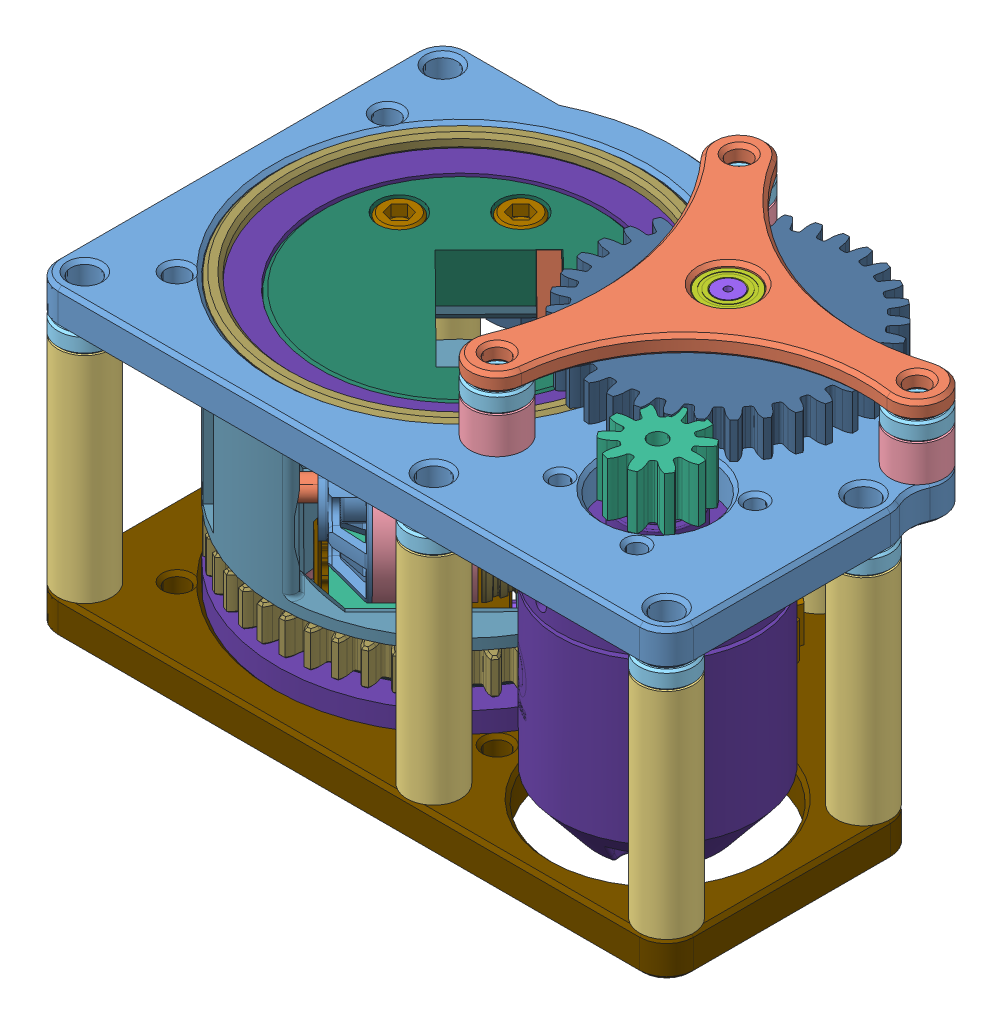
SolidWorks assembly Teathered Swerve Outer Modual Assem, configuration Default. Lengths in mm.
Overall size (127.68 94.78 93.36).
160 component instances, 50 part files, 75 mates.
Components (placement in the parent):
- Teathered Swerve Outer Modual-1: Teathered Swerve Outer Modual [Sketch Only] at origin
- Teathered Swerve Assem-1: Teathered Swerve Assem [Default] at (0 19.05 0) x (0.703653 0 -0.710544) z (0.710544 0 0.703653) size (65 79.59 67.05)
  - Teathered Swerve Inner Structure-1: Teathered Swerve Inner Structure [Default] at origin
  - BA-2310-Motor.STEP-1: BA-2310-Motor.STEP [Default] at (13.218 51.7723 56.3355) x (0 0.707107 0.707107) z (-1 0 0) size (29.1 29.1 46)
    - 2310-Rotor-Assem.STEP-1: 2310-Rotor-Assem.STEP [Default] at (14.7295 2.66 3.5453) size (29.1 29.1 46)
      - 23mm-Endbell.STEP-1: 23mm-Endbell.STEP [Default] at (-57.7218 14.2616 14.8949) size (29.1 29.1 12.75)
      - 2310-Shaft.STEP-1: 2310-Shaft.STEP [Default] at (-57.7218 14.2616 -15.3551) size (4 4 46)
      - 2310-Magnet.STEP-1: 2310-Magnet.STEP [Default] at (-57.7218 14.2616 8.6449) size (4 1.65 10)
      - 2310-Magnet.STEP-2: 2310-Magnet.STEP [Default] at (-57.7218 14.2616 8.6449) x (0.900969 0.433884 0) z (0 0 1) size (4 1.65 10)
      - 2310-Magnet.STEP-3: 2310-Magnet.STEP [Default] at (-57.7218 14.2616 8.6449) x (0.62349 0.781831 0) z (0 0 1) size (4 1.65 10)
      - 2310-Magnet.STEP-4: 2310-Magnet.STEP [Default] at (-57.7218 14.2616 8.6449) x (0.222521 0.974928 0) z (0 0 1) size (4 1.65 10)
      - 2310-Magnet.STEP-5: 2310-Magnet.STEP [Default] at (-57.7218 14.2616 8.6449) x (-0.222521 0.974928 0) z (0 0 1) size (4 1.65 10)
      - 2310-Magnet.STEP-6: 2310-Magnet.STEP [Default] at (-57.7218 14.2616 8.6449) x (-0.62349 0.781831 0) z (0 0 1) size (4 1.65 10)
      - 2310-Magnet.STEP-7: 2310-Magnet.STEP [Default] at (-57.7218 14.2616 8.6449) x (-0.900969 0.433884 0) z (0 0 1) size (4 1.65 10)
      - 2310-Magnet.STEP-8: 2310-Magnet.STEP [Default] at (-57.7218 14.2616 8.6449) x (-1 0 0) z (0 0 1) size (4 1.65 10)
      - 2310-Magnet.STEP-9: 2310-Magnet.STEP [Default] at (-57.7218 14.2616 8.6449) x (-0.900969 -0.433884 0) z (0 0 1) size (4 1.65 10)
      - 2310-Magnet.STEP-10: 2310-Magnet.STEP [Default] at (-57.7218 14.2616 8.6449) x (-0.62349 -0.781831 0) z (0 0 1) size (4 1.65 10)
      - 2310-Magnet.STEP-11: 2310-Magnet.STEP [Default] at (-57.7218 14.2616 8.6449) x (-0.222521 -0.974928 0) z (0 0 1) size (4 1.65 10)
      - 2310-Magnet.STEP-12: 2310-Magnet.STEP [Default] at (-57.7218 14.2616 8.6449) x (0.222521 -0.974928 0) z (0 0 1) size (4 1.65 10)
      - 2310-Magnet.STEP-13: 2310-Magnet.STEP [Default] at (-57.7218 14.2616 8.6449) x (0.62349 -0.781831 0) z (0 0 1) size (4 1.65 10)
      - 2310-Magnet.STEP-14: 2310-Magnet.STEP [Default] at (-57.7218 14.2616 8.6449) x (0.900969 -0.433884 0) z (0 0 1) size (4 1.65 10)
      - 2310-Fluxring.STEP-1: 2310-Fluxring.STEP [Default] at (-57.7218 14.2616 7.6449) size (29.1 29.1 13.25)
    - 2310-Stator-Assem.STEP-1: 2310-Stator-Assem.STEP [Default] at (-38.1007 -3.4232 24.6837) size (29.1 29.1 19.5)
      - 23x10x10mm-Stator.STEP-1: 23x10x10mm-Stator.STEP [Default] at (52.3253 8.3812 -27.0554) size (23 23 10)
        - 23x10x5mm-Stator.STEP-1: 23x10x5mm-Stator.STEP [Default] at (-16.2466 9.1923 4.328) size (23 23 5)
          - 23x10x1mm-Stator.STEP-1: 23x10x1mm-Stator.STEP [Default] at (-15.1244 2.7036 6.5442) size (23 23 1)
            - 23x10-Stator-Plate.STEP-1: 23x10-Stator-Plate.STEP [Default] at (-25.8459 0.0676 13.4926) size (23 23 0.2)
            - 23x10-Stator-Plate.STEP-2: 23x10-Stator-Plate.STEP [Default] at (-25.8459 0.0676 13.2926) size (23 23 0.2)
            - 23x10-Stator-Plate.STEP-3: 23x10-Stator-Plate.STEP [Default] at (-25.8459 0.0676 13.0926) size (23 23 0.2)
            - 23x10-Stator-Plate.STEP-4: 23x10-Stator-Plate.STEP [Default] at (-25.8459 0.0676 12.8926) size (23 23 0.2)
            - 23x10-Stator-Plate.STEP-5: 23x10-Stator-Plate.STEP [Default] at (-25.8459 0.0676 12.6926) size (23 23 0.2)
          - 23x10x1mm-Stator.STEP-2: 23x10x1mm-Stator.STEP [Default] at (-15.1244 2.7036 5.5442) size (23 23 1)
            - 23x10-Stator-Plate.STEP-1: 23x10-Stator-Plate.STEP [Default] at (-25.8459 0.0676 13.4926) size (23 23 0.2)
            - 23x10-Stator-Plate.STEP-2: 23x10-Stator-Plate.STEP [Default] at (-25.8459 0.0676 13.2926) size (23 23 0.2)
            - 23x10-Stator-Plate.STEP-3: 23x10-Stator-Plate.STEP [Default] at (-25.8459 0.0676 13.0926) size (23 23 0.2)
            - 23x10-Stator-Plate.STEP-4: 23x10-Stator-Plate.STEP [Default] at (-25.8459 0.0676 12.8926) size (23 23 0.2)
            - 23x10-Stator-Plate.STEP-5: 23x10-Stator-Plate.STEP [Default] at (-25.8459 0.0676 12.6926) size (23 23 0.2)
          - 23x10x1mm-Stator.STEP-3: 23x10x1mm-Stator.STEP [Default] at (-15.1244 2.7036 4.5442) size (23 23 1)
            - 23x10-Stator-Plate.STEP-1: 23x10-Stator-Plate.STEP [Default] at (-25.8459 0.0676 13.4926) size (23 23 0.2)
            - 23x10-Stator-Plate.STEP-2: 23x10-Stator-Plate.STEP [Default] at (-25.8459 0.0676 13.2926) size (23 23 0.2)
            - 23x10-Stator-Plate.STEP-3: 23x10-Stator-Plate.STEP [Default] at (-25.8459 0.0676 13.0926) size (23 23 0.2)
            - 23x10-Stator-Plate.STEP-4: 23x10-Stator-Plate.STEP [Default] at (-25.8459 0.0676 12.8926) size (23 23 0.2)
            - 23x10-Stator-Plate.STEP-5: 23x10-Stator-Plate.STEP [Default] at (-25.8459 0.0676 12.6926) size (23 23 0.2)
          - 23x10x1mm-Stator.STEP-4: 23x10x1mm-Stator.STEP [Default] at (-15.1244 2.7036 3.5442) size (23 23 1)
            - 23x10-Stator-Plate.STEP-1: 23x10-Stator-Plate.STEP [Default] at (-25.8459 0.0676 13.4926) size (23 23 0.2)
            - 23x10-Stator-Plate.STEP-2: 23x10-Stator-Plate.STEP [Default] at (-25.8459 0.0676 13.2926) size (23 23 0.2)
            - 23x10-Stator-Plate.STEP-3: 23x10-Stator-Plate.STEP [Default] at (-25.8459 0.0676 13.0926) size (23 23 0.2)
            - 23x10-Stator-Plate.STEP-4: 23x10-Stator-Plate.STEP [Default] at (-25.8459 0.0676 12.8926) size (23 23 0.2)
            - 23x10-Stator-Plate.STEP-5: 23x10-Stator-Plate.STEP [Default] at (-25.8459 0.0676 12.6926) size (23 23 0.2)
          - 23x10x1mm-Stator.STEP-5: 23x10x1mm-Stator.STEP [Default] at (-15.1244 2.7036 2.5442) size (23 23 1)
            - 23x10-Stator-Plate.STEP-1: 23x10-Stator-Plate.STEP [Default] at (-25.8459 0.0676 13.4926) size (23 23 0.2)
            - 23x10-Stator-Plate.STEP-2: 23x10-Stator-Plate.STEP [Default] at (-25.8459 0.0676 13.2926) size (23 23 0.2)
            - 23x10-Stator-Plate.STEP-3: 23x10-Stator-Plate.STEP [Default] at (-25.8459 0.0676 13.0926) size (23 23 0.2)
            - 23x10-Stator-Plate.STEP-4: 23x10-Stator-Plate.STEP [Default] at (-25.8459 0.0676 12.8926) size (23 23 0.2)
            - 23x10-Stator-Plate.STEP-5: 23x10-Stator-Plate.STEP [Default] at (-25.8459 0.0676 12.6926) size (23 23 0.2)
        - 23x10x5mm-Stator.STEP-2: 23x10x5mm-Stator.STEP [Default] at (-16.2466 9.1923 -0.672) size (23 23 5)
          - 23x10x1mm-Stator.STEP-1: 23x10x1mm-Stator.STEP [Default] at (-15.1244 2.7036 6.5442) size (23 23 1)
            - 23x10-Stator-Plate.STEP-1: 23x10-Stator-Plate.STEP [Default] at (-25.8459 0.0676 13.4926) size (23 23 0.2)
            - 23x10-Stator-Plate.STEP-2: 23x10-Stator-Plate.STEP [Default] at (-25.8459 0.0676 13.2926) size (23 23 0.2)
            - 23x10-Stator-Plate.STEP-3: 23x10-Stator-Plate.STEP [Default] at (-25.8459 0.0676 13.0926) size (23 23 0.2)
            - 23x10-Stator-Plate.STEP-4: 23x10-Stator-Plate.STEP [Default] at (-25.8459 0.0676 12.8926) size (23 23 0.2)
            - 23x10-Stator-Plate.STEP-5: 23x10-Stator-Plate.STEP [Default] at (-25.8459 0.0676 12.6926) size (23 23 0.2)
          - 23x10x1mm-Stator.STEP-2: 23x10x1mm-Stator.STEP [Default] at (-15.1244 2.7036 5.5442) size (23 23 1)
            - 23x10-Stator-Plate.STEP-1: 23x10-Stator-Plate.STEP [Default] at (-25.8459 0.0676 13.4926) size (23 23 0.2)
            - 23x10-Stator-Plate.STEP-2: 23x10-Stator-Plate.STEP [Default] at (-25.8459 0.0676 13.2926) size (23 23 0.2)
            - 23x10-Stator-Plate.STEP-3: 23x10-Stator-Plate.STEP [Default] at (-25.8459 0.0676 13.0926) size (23 23 0.2)
            - 23x10-Stator-Plate.STEP-4: 23x10-Stator-Plate.STEP [Default] at (-25.8459 0.0676 12.8926) size (23 23 0.2)
            - 23x10-Stator-Plate.STEP-5: 23x10-Stator-Plate.STEP [Default] at (-25.8459 0.0676 12.6926) size (23 23 0.2)
          - 23x10x1mm-Stator.STEP-3: 23x10x1mm-Stator.STEP [Default] at (-15.1244 2.7036 4.5442) size (23 23 1)
            - 23x10-Stator-Plate.STEP-1: 23x10-Stator-Plate.STEP [Default] at (-25.8459 0.0676 13.4926) size (23 23 0.2)
            - 23x10-Stator-Plate.STEP-2: 23x10-Stator-Plate.STEP [Default] at (-25.8459 0.0676 13.2926) size (23 23 0.2)
            - 23x10-Stator-Plate.STEP-3: 23x10-Stator-Plate.STEP [Default] at (-25.8459 0.0676 13.0926) size (23 23 0.2)
            - 23x10-Stator-Plate.STEP-4: 23x10-Stator-Plate.STEP [Default] at (-25.8459 0.0676 12.8926) size (23 23 0.2)
            - 23x10-Stator-Plate.STEP-5: 23x10-Stator-Plate.STEP [Default] at (-25.8459 0.0676 12.6926) size (23 23 0.2)
          - 23x10x1mm-Stator.STEP-4: 23x10x1mm-Stator.STEP [Default] at (-15.1244 2.7036 3.5442) size (23 23 1)
            - 23x10-Stator-Plate.STEP-1: 23x10-Stator-Plate.STEP [Default] at (-25.8459 0.0676 13.4926) size (23 23 0.2)
            - 23x10-Stator-Plate.STEP-2: 23x10-Stator-Plate.STEP [Default] at (-25.8459 0.0676 13.2926) size (23 23 0.2)
            - 23x10-Stator-Plate.STEP-3: 23x10-Stator-Plate.STEP [Default] at (-25.8459 0.0676 13.0926) size (23 23 0.2)
            - 23x10-Stator-Plate.STEP-4: 23x10-Stator-Plate.STEP [Default] at (-25.8459 0.0676 12.8926) size (23 23 0.2)
            - 23x10-Stator-Plate.STEP-5: 23x10-Stator-Plate.STEP [Default] at (-25.8459 0.0676 12.6926) size (23 23 0.2)
          - 23x10x1mm-Stator.STEP-5: 23x10x1mm-Stator.STEP [Default] at (-15.1244 2.7036 2.5442) size (23 23 1)
            - 23x10-Stator-Plate.STEP-1: 23x10-Stator-Plate.STEP [Default] at (-25.8459 0.0676 13.4926) size (23 23 0.2)
            - 23x10-Stator-Plate.STEP-2: 23x10-Stator-Plate.STEP [Default] at (-25.8459 0.0676 13.2926) size (23 23 0.2)
            - 23x10-Stator-Plate.STEP-3: 23x10-Stator-Plate.STEP [Default] at (-25.8459 0.0676 13.0926) size (23 23 0.2)
            - 23x10-Stator-Plate.STEP-4: 23x10-Stator-Plate.STEP [Default] at (-25.8459 0.0676 12.8926) size (23 23 0.2)
            - 23x10-Stator-Plate.STEP-5: 23x10-Stator-Plate.STEP [Default] at (-25.8459 0.0676 12.6926) size (23 23 0.2)
      - 4x11x4-BRG.STEP-1: 4x11x4-BRG.STEP [Default] at (-4.8916 20.3447 -18.4846) x (0 0 1) z (-0.998854 -0.047866 0) size (3.99 11 11)
        - 694HZZ_SOLID_1-1.STEP-1: 694HZZ_SOLID_1-1.STEP [Default] at origin size (3.99 6.18 6.18)
        - 694HZZ_SOLID_2-1.STEP-1: 694HZZ_SOLID_2-1.STEP [Default] at origin size (3.99 11 11)
        - 694HZZ_SOLID_3-1.STEP-1: 694HZZ_SOLID_3-1.STEP [Default] at origin size (2.34 9.37 9.37)
      - 4x8x3-BRG.STEP-1: 4x8x3-BRG.STEP [Default] at (-4.8916 20.3447 -2.9921) x (0 0 -1) z (0.838857 -0.544351 0) size (3 8 8)
        - SMR84ZZ_SOLID_1.STEP-1: SMR84ZZ_SOLID_1.STEP [Default] at origin size (3 5.01 5.01)
        - SMR84ZZ_SOLID_2.STEP-1: SMR84ZZ_SOLID_2.STEP [Default] at origin size (3 8 8)
        - SMR84ZZ_SOLID_3.STEP-1: SMR84ZZ_SOLID_3.STEP [Default] at origin size (1.76 7.4 7.4)
      - 2310-Mount.STEP-1: 2310-Mount.STEP [Default] at (-4.8916 20.3447 -20.9907) size (29.1 29.1 19.5)
    - Spacer-4mm.STEP-1: Spacer-4mm.STEP [Default] at (-42.9923 16.9215 23.1902) size (6 6 0.25)
    - Spacer-4mm.STEP-2: Spacer-4mm.STEP [Default] at (-42.9923 16.9215 3.9552) size (6 6 0.25)
    - C-Clip-4mm_98541A112.STEP-1: C-Clip-4mm_98541A112.STEP [Default] at (-42.9923 16.9215 3.7402) x (0 0 -1) z (0.963178 -0.268866 0) size (0.4 6.8 5.16)
    - Collar-4mm.STEP-1: Collar-4mm.STEP [Default] at (-42.9923 16.9215 -1.4598) x (0 1 0) z (0 0 1) size (8.5 8.5 5)
    - M2.5x3-SetScrew.STEP-1: M2.5x3-SetScrew.STEP [Default] at (-42.9923 20.0215 0.7902) x (0.871933 0 -0.489626) z (0 1 0) size (2.89 2.5 3.01)
  - Zoro Bearing 50mmID 65mm OD 7mmWidth-1: Zoro Bearing 50mmID 65mm OD 7mmWidth [Default] at (0 50.475 0) size (65 7 65)
  - Zoro Bearing 50mmID 65mm OD 7mmWidth-2: Zoro Bearing 50mmID 65mm OD 7mmWidth [Default] at (0 8.55 0) size (65 7 65)
  - Wheel with Pully-1: Wheel with Pully [Default] x (0 -0.449614 0.893223) z (0 -0.893223 -0.449614) size (38.1 24.77 38.1)
  - Inner Modual Intermediate Shaft-1: Inner Modual Intermediate Shaft [Default] at (1.7272 27.4182 -7.2941) x (0 -0.995575 -0.093965) z (0 -0.093965 0.995575) size (5.5 53.85 4.76)
  - Drive Stage 1 Pinion-1: Drive Stage 1 Pinion [Aluminum Version] at (17.8528 33.3375 13.97) x (0 0.98945 0.144875) z (0 0.144875 -0.98945) size (8.79 6.35 8.54)
  - Drive Stage 2 Pinion-1: Drive Stage 2 Pinion [Default] at (-12.1285 27.4182 -7.2941) x (0 -0.995575 -0.093965) z (0 -0.093965 0.995575) size (10.57 36.37 10.57)
  - Drive Stage 1 Pully-1: Drive Stage 1 Pully [Default] at (17.9578 27.4182 -7.2941) x (0 -0.995575 -0.093965) z (0 -0.093965 0.995575) size (24.89 10.48 24.89)
  - Drive Stage 1 Belt-1: Drive Stage 1 Belt [Default] at (17.9578 33.3375 13.97) x (1 0 0) z (0 0.268176 0.96337) size (6 27.13 41.27)
  - Drive Stage 2 Belt-1: Drive Stage 2 Belt [Default] at (-12.1285 27.4182 -7.2941) x (1 0 0) z (0 0.966388 -0.257089) size (9 31.9 49.96)
  - 60355K861_Ball Bearing-1: 60355K861_Ball Bearing [60355K861] at (26.162 27.4182 -7.2941) x (0 0 -1) z (1 0 0) size (12.7 12.7 4.98)
  - 60355K861_Ball Bearing-2: 60355K861_Ball Bearing [60355K861] at (-22.7838 27.4182 -7.2941) x (0 0.531717 -0.846922) z (1 0 0) size (12.7 12.7 4.98)
  - Wheel Shaft-1: Wheel Shaft [Default] x (0 0 1) z (1 0 0) size (9.53 10.25 47.62)
  - socket head cap screw_ai-4: socket head cap screw_ai [HX-SHCS 0.164-32x0.375x0.375-N] at (23.2156 17.13 10.795) x (-1 0 0) z (0 0.924225 0.381849) size (13.69 6.86 6.86)
  - socket head cap screw_ai-7: socket head cap screw_ai [HX-SHCS 0.164-32x0.375x0.375-N] at (23.2156 49.53 5.715) x (-1 0 0) z (0 0.924225 0.381849) size (13.69 6.86 6.86)
  - socket head cap screw_ai-8: socket head cap screw_ai [HX-SHCS 0.164-32x0.375x0.375-N] at (23.2156 49.53 -1.905) x (-1 0 0) z (0 0.924225 0.381849) size (13.69 6.86 6.86)
  - socket head cap screw_ai-10: socket head cap screw_ai [HX-SHCS 0.138-32x0.375x0.375-N] at (16.8402 26.6677 21.0887) x (0 -1 0) z (0 0 1) size (13.03 5.74 5.74)
  - socket head cap screw_ai-11: socket head cap screw_ai [HX-SHCS 0.138-32x0.375x0.375-N] at (8.255 26.6677 -25.694) x (0 -1 0) z (0 0 1) size (13.03 5.74 5.74)
  - socket head cap screw_ai-12: socket head cap screw_ai [HX-SHCS 0.138-32x0.375x0.375-N] at (-15.24 26.6677 -22.2726) x (0 -1 0) z (0 0 1) size (13.03 5.74 5.74)
  - socket head cap screw_ai-13: socket head cap screw_ai [HX-SHCS 0.138-32x0.375x0.375-N] at (-26.2298 26.6677 6.35) x (0 -1 0) z (0 0 1) size (13.03 5.74 5.74)
  - machine screw nut hex_ai-6: machine screw nut hex_ai [MSHXNUT 0.164-32-S-N] at (-7.62 38.9105 -16.51) x (1 0 0) z (0 -1 0) size (8.74 10.09 3.3)
  - machine screw nut hex_ai-7: machine screw nut hex_ai [MSHXNUT 0.164-32-S-N] at (7.62 38.9105 -16.51) x (1 0 0) z (0 -1 0) size (8.74 10.09 3.3)
  - socket head cap screw_ai-16: socket head cap screw_ai [HX-SHCS 0.164-32x0.5x0.5-N] at (7.62 53.975 -16.51) x (0 -1 0) z (0 0 1) size (16.87 6.86 6.86)
  - socket head cap screw_ai-17: socket head cap screw_ai [HX-SHCS 0.164-32x0.5x0.5-N] at (-7.62 53.975 -16.51) x (0 -1 0) z (0 0 1) size (16.87 6.86 6.86)
  - Drive Motor Mount-1: Drive Motor Mount [Default] at origin size (3.17 41.93 34.92)
  - Final Steer Gear-1: Final Steer Gear [Default] at origin size (64.76 6.35 64.73)
  - Inner Structure Bottom-1: Inner Structure Bottom [Default] at origin size (56.35 17.75 56.35)
  - Inner Structure Mid-1: Inner Structure Mid [Default] at origin size (65 46.99 65)
  - Inner Structure Top-1: Inner Structure Top [Default] at origin size (56.52 8.59 56.35)
  - .375 Thunder Hex Bearing-2: .375 Thunder Hex Bearing [Default] at (-18.4023 0 0) x (1 0 0) z (0 -0.11391 0.993491) size (7.11 24.61 24.61)
  - .375 Thunder Hex Bearing-3: .375 Thunder Hex Bearing [Default] at (6.3373 0 0) x (-1 0 0) z (0 -0.999894 -0.014533) size (7.11 24.61 24.61)
- NEO 550-1: NEO 550 [Default] at (50.8 80.7 15.875) x (0 -1 0) z (0.838671 0 -0.544639) size (56.01 42.91 43.01)
- Outer Bottom Plate-1: Outer Bottom Plate [Default] at origin size (112.71 6.8 76.95)
- Outer Top Plate - Test - PLA-1: Outer Top Plate - Test - PLA [Default] at origin size (112.71 6.8 76.95)
- Stage 2 Retaining Plate-1: Stage 2 Retaining Plate [Default] at origin size (60.04 3.17 61.41)
- RB Standoff_-15: RB Standoff_ [1500L] at (69.85 46.975 33.3375) size (9.53 38.1 9.53)
- RB Spacer_-5: RB Spacer_ [0250L] at (69.85 78.725 -11.1125) size (9.53 6.35 9.53)
- RB Standoff_-11: RB Standoff_ [1500L] at (69.85 46.975 -1.5875) x (0.982082 0 -0.188455) z (0.188455 0 0.982082) size (9.53 38.1 9.53)
- RB Standoff_-10: RB Standoff_ [1500L] at (33.3375 46.975 -30.1625) x (0.918365 0 -0.395734) z (0.395734 0 0.918365) size (9.53 38.1 9.53)
- RB Standoff_-14: RB Standoff_ [1500L] at (28.575 46.975 33.3375) x (0.8 0 -0.6) z (0.6 0 0.8) size (9.53 38.1 9.53)
- RB Standoff_-13: RB Standoff_ [1500L] at (-33.3375 46.975 33.3375) x (0.63358 0 -0.773678) z (0.773678 0 0.63358) size (9.53 38.1 9.53)
- RB Standoff_-12: RB Standoff_ [1500L] at (-33.3375 46.975 -30.1625) x (0.263225 0 -0.964735) z (0.964735 0 0.263225) size (9.53 38.1 9.53)
- RB Spacer_-4: RB Spacer_ [0250L] at (19.3325 78.725 -30.0582) x (0.982082 0 -0.188455) z (0.188455 0 0.982082) size (9.53 6.35 9.53)
- RB Spacer_-3: RB Spacer_ [0250L] at (28.2957 78.725 21.831) x (0.918365 0 -0.395734) z (0.395734 0 0.918365) size (9.53 6.35 9.53)
- .125'' Spacer-1: .125'' Spacer [Default] at (69.85 67.6125 33.3375) size (9.53 3.17 9.53)
- .125'' Spacer-2: .125'' Spacer [Default] at (69.85 67.6125 -1.5875) x (0.982082 0 -0.188455) z (0.188455 0 0.982082) size (9.53 3.17 9.53)
- .125'' Spacer-3: .125'' Spacer [Default] at (33.3375 67.6125 -30.1625) x (0.918365 0 -0.395734) z (0.395734 0 0.918365) size (9.53 3.17 9.53)
- .125'' Spacer-4: .125'' Spacer [Default] at (28.575 67.6125 33.3375) x (0.8 0 -0.6) z (0.6 0 0.8) size (9.53 3.17 9.53)
- .125'' Spacer-5: .125'' Spacer [Default] at (-33.3375 67.6125 33.3375) x (0.63358 0 -0.773678) z (0.773678 0 0.63358) size (9.53 3.17 9.53)
- .125'' Spacer-7: .125'' Spacer [Default] at (-33.3375 67.6125 -30.1625) x (0.263225 0 -0.964735) z (0.964735 0 0.263225) size (9.53 3.17 9.53)
- .125'' Spacer-9: .125'' Spacer [Default] at (28.2957 83.4875 21.831) x (0.243009 0 -0.970024) z (0.970024 0 0.243009) size (9.53 3.17 9.53)
- .125'' Spacer-10: .125'' Spacer [Default] at (19.3325 83.4875 -30.0582) x (0.055848 0 -0.998439) z (0.998439 0 0.055848) size (9.53 3.17 9.53)
- .125'' Spacer-11: .125'' Spacer [Default] at (69.85 83.4875 -11.1125) x (-0.160701 0 -0.987003) z (0.987003 0 -0.160701) size (9.53 3.17 9.53)
- Steer Motor Pinion-1: Steer Motor Pinion [Default] at (50.8 78.4625 15.875) x (0.347395 0 0.937719) z (0 1 0) size (15.24 14.85 9.53)
- 57155K319_Stainless Steel Ball Bearing-1: 57155K319_Stainless Steel Ball Bearing [57155K319] at (38.3007 85.9005 -9.1132) x (1 0 0) z (0 1 0) size (10.72 10.72 3.17)
- 57155K319_Stainless Steel Ball Bearing-2: 57155K319_Stainless Steel Ball Bearing [57155K319] at (38.3007 27.0995 -9.1132) x (1 0 0) z (0 -1 0) size (10.72 10.72 3.17)
- Outer Modual Intermediate Shaft-1: Outer Modual Intermediate Shaft [Default] at (38.3007 56.5 -9.1132) x (0.705701 0 -0.70851) z (0.70851 0 0.705701) size (5.5 61.98 4.76)
- Steer Intermediate Pinion-1: Steer Intermediate Pinion [Default] at (38.3007 35.8752 -9.1132) x (0.260737 0 0.96541) z (0 -1 0) size (18.9 19.02 10.36)
- Steer Intermediate Gear-1: Steer Intermediate Gear [Default] at (38.3007 80.3252 -9.1132) x (-0.260737 0 -0.96541) z (0 1 0) size (45.72 45.61 48.44)
- Bottom Bearing Retainer-1: Bottom Bearing Retainer [Default] at origin size (64.75 2.52 64.75)
- Top Bearing Retainer-1: Top Bearing Retainer [Default] at origin size (64.75 2.52 64.75)
Mates (geometry in assembly coordinates):
- Coincident1: coincident aligned: plane of Teathered Swerve Outer Modual-1 through (0 0 0) normal (0 0 1)
- Coincident2: coincident aligned: plane of Teathered Swerve Outer Modual-1 through (0 0 0) normal (0 1 0)
- Coincident3: coincident aligned: plane of Teathered Swerve Outer Modual-1 through (0 0 0) normal (1 0 0)
- Coincident4: coincident anti-aligned: circle of Teathered Swerve Outer Modual-1; cylinder of Teathered Swerve Assem-1/Zoro Bearing 50mmID 65mm OD 7mmWidth-1 through (0 73.025 0) axis (0 -1 0) radius 32.5
- Coincident5: coincident: line of Teathered Swerve Outer Modual-1 through (65 -32.5 66.025) axis (0 1 0); plane of Teathered Swerve Assem-1/Zoro Bearing 50mmID 65mm OD 7mmWidth-1 through (0 66.025 0) normal (0 -1 0)
- Coincident6: coincident: line of Teathered Swerve Outer Modual-1 through (139.7 -38.1 69.2) axis (0 1 0); plane of NEO 550-1 through (47.2598 69.2 10.4236) normal (0 1 0)
- Coincident7: coincident aligned: plane of Outer Bottom Plate-1 through (0 0 0) normal (0 1 0)
- Coincident8: coincident aligned: plane of Outer Bottom Plate-1 through (0 0 0) normal (0 0 1)
- Coincident9: coincident aligned: plane of Outer Bottom Plate-1 through (0 0 0) normal (1 0 0)
- Coincident10: coincident aligned: plane of Outer Top Plate-1 through (0 0 0) normal (0 0 1)
- Coincident11: coincident aligned: plane of Outer Top Plate-1 through (0 0 0) normal (0 1 0)
- Coincident12: coincident aligned: plane of Outer Top Plate-1 through (0 0 0) normal (1 0 0)
- Coincident13: coincident aligned: plane of Stage 2 Retaining Plate-1 through (0 0 0) normal (0 0 1)
- Coincident14: coincident aligned: plane of Stage 2 Retaining Plate-1 through (0 0 0) normal (0 1 0)
- Coincident15: coincident aligned: plane of Stage 2 Retaining Plate-1 through (0 0 0) normal (1 0 0)
- Coincident18: coincident anti-aligned: plane of Outer Bottom Plate-1 through (-33.3375 27.925 33.3375) normal (0 1 0); plane of RB Standoff_-15 through (69.85 27.925 33.3375) normal (0 -1 0)
- Concentric4: concentric anti-aligned: cylinder of Outer Bottom Plate-1 through (69.85 21.575 33.3375) axis (0 1 0) radius 2.4892; cylinder of RB Standoff_-15 through (69.85 66.025 33.3375) axis (0 -1 0) radius 4.7625
- Concentric5: concentric aligned: cylinder of Outer Top Plate-1 through (69.85 75.55 -11.1125) axis (0 -1 0) radius 2.0193; cylinder of RB Spacer_-5 through (69.85 81.9 -11.1125) axis (0 -1 0) radius 4.7625
- Coincident19: coincident anti-aligned: plane of Outer Top Plate-1 through (-33.3375 75.55 33.3375) normal (0 1 0); plane of RB Spacer_-5 through (69.85 75.55 -11.1125) normal (0 -1 0)
- Coincident20: coincident anti-aligned: plane of Outer Bottom Plate-1 through (-33.3375 27.925 33.3375) normal (0 1 0); plane of RB Standoff_-11 through (69.85 27.925 -1.5875) normal (0 -1 0)
- Coincident21: coincident anti-aligned: plane of Outer Bottom Plate-1 through (-33.3375 27.925 33.3375) normal (0 1 0); plane of RB Standoff_-10 through (33.3375 27.925 -30.1625) normal (0 -1 0)
- Coincident22: coincident anti-aligned: plane of Outer Bottom Plate-1 through (-33.3375 27.925 33.3375) normal (0 1 0); plane of RB Standoff_-14 through (28.575 27.925 33.3375) normal (0 -1 0)
- Coincident23: coincident anti-aligned: plane of Outer Bottom Plate-1 through (-33.3375 27.925 33.3375) normal (0 1 0); plane of RB Standoff_-13 through (-33.3375 27.925 33.3375) normal (0 -1 0)
- Coincident25: coincident anti-aligned: plane of Outer Bottom Plate-1 through (-33.3375 27.925 33.3375) normal (0 1 0); plane of RB Standoff_-12 through (-33.3375 27.925 -30.1625) normal (0 -1 0)
- Concentric6: concentric aligned: cylinder of Outer Top Plate-1 through (69.85 75.55 -1.5875) axis (0 -1 0) radius 2.4892; cylinder of RB Standoff_-11 through (69.85 66.025 -1.5875) axis (0 -1 0) radius 4.7625
- Concentric7: concentric aligned: cylinder of Outer Top Plate-1 through (33.3375 75.55 -30.1625) axis (0 -1 0) radius 2.4892; cylinder of RB Standoff_-10 through (33.3375 66.025 -30.1625) axis (0 -1 0) radius 4.7625
- Concentric8: concentric aligned: cylinder of Outer Top Plate-1 through (28.575 75.55 33.3375) axis (0 -1 0) radius 2.4892; cylinder of RB Standoff_-14 through (28.575 66.025 33.3375) axis (0 -1 0) radius 4.7625
- Concentric9: concentric aligned: cylinder of Outer Top Plate-1 through (-33.3375 75.55 33.3375) axis (0 -1 0) radius 2.4892; cylinder of RB Standoff_-13 through (-33.3375 66.025 33.3375) axis (0 -1 0) radius 4.7625
- Concentric11: concentric aligned: cylinder of Outer Top Plate-1 through (-33.3375 75.55 -30.1625) axis (0 -1 0) radius 2.4892; cylinder of RB Standoff_-12 through (-33.3375 66.025 -30.1625) axis (0 -1 0) radius 4.7625
- Coincident27: coincident anti-aligned: plane of Outer Top Plate-1 through (-33.3375 75.55 33.3375) normal (0 1 0); plane of RB Spacer_-4 through (19.3325 75.55 -30.0582) normal (0 -1 0)
- Coincident28: coincident anti-aligned: plane of Outer Top Plate-1 through (-33.3375 75.55 33.3375) normal (0 1 0); plane of RB Spacer_-3 through (28.2957 75.55 21.831) normal (0 -1 0)
- Concentric12: concentric aligned: cylinder of Outer Top Plate-1 through (19.3325 75.55 -30.0582) axis (0 -1 0) radius 2.0193; cylinder of RB Spacer_-4 through (19.3325 81.9 -30.0582) axis (0 -1 0) radius 4.7625
- Concentric13: concentric aligned: cylinder of Outer Top Plate-1 through (28.2957 75.55 21.831) axis (0 -1 0) radius 2.0193; cylinder of RB Spacer_-3 through (28.2957 81.9 21.831) axis (0 -1 0) radius 4.7625
- Coincident30: coincident anti-aligned: plane of RB Standoff_-15 through (69.85 66.025 33.3375) normal (0 1 0); plane of .125'' Spacer-1 through (69.85 66.025 33.3375) normal (0 -1 0)
- Concentric14: concentric aligned: cylinder of RB Standoff_-15 through (69.85 66.025 33.3375) axis (0 -1 0) radius 4.7625; cylinder of .125'' Spacer-1 through (69.85 69.2 33.3375) axis (0 -1 0) radius 4.7625
- Coincident31: coincident anti-aligned: plane of RB Standoff_-15 through (69.85 66.025 33.3375) normal (0 1 0); plane of .125'' Spacer-2 through (69.85 66.025 -1.5875) normal (0 -1 0)
- Coincident32: coincident anti-aligned: plane of RB Standoff_-15 through (69.85 66.025 33.3375) normal (0 1 0); plane of .125'' Spacer-3 through (33.3375 66.025 -30.1625) normal (0 -1 0)
- Coincident33: coincident anti-aligned: plane of RB Standoff_-15 through (69.85 66.025 33.3375) normal (0 1 0); plane of .125'' Spacer-4 through (28.575 66.025 33.3375) normal (0 -1 0)
- Coincident34: coincident anti-aligned: plane of RB Standoff_-15 through (69.85 66.025 33.3375) normal (0 1 0); plane of .125'' Spacer-5 through (-33.3375 66.025 33.3375) normal (0 -1 0)
- Coincident36: coincident anti-aligned: plane of RB Standoff_-15 through (69.85 66.025 33.3375) normal (0 1 0); plane of .125'' Spacer-7 through (-33.3375 66.025 -30.1625) normal (0 -1 0)
- Concentric15: concentric aligned: cylinder of RB Standoff_-11 through (69.85 66.025 -1.5875) axis (0 -1 0) radius 4.7625; cylinder of .125'' Spacer-2 through (69.85 69.2 -1.5875) axis (0 -1 0) radius 4.7625
- Concentric16: concentric aligned: cylinder of RB Standoff_-10 through (33.3375 66.025 -30.1625) axis (0 -1 0) radius 4.7625; cylinder of .125'' Spacer-3 through (33.3375 69.2 -30.1625) axis (0 -1 0) radius 4.7625
- Concentric17: concentric aligned: cylinder of RB Standoff_-14 through (28.575 66.025 33.3375) axis (0 -1 0) radius 4.7625; cylinder of .125'' Spacer-4 through (28.575 69.2 33.3375) axis (0 -1 0) radius 4.7625
- Concentric18: concentric aligned: cylinder of RB Standoff_-13 through (-33.3375 66.025 33.3375) axis (0 -1 0) radius 4.7625; cylinder of .125'' Spacer-5 through (-33.3375 69.2 33.3375) axis (0 -1 0) radius 4.7625
- Concentric20: concentric aligned: cylinder of RB Standoff_-12 through (-33.3375 66.025 -30.1625) axis (0 -1 0) radius 4.7625; cylinder of .125'' Spacer-7 through (-33.3375 69.2 -30.1625) axis (0 -1 0) radius 4.7625
- Concentric21: concentric aligned: cylinder of RB Spacer_-3 through (28.2957 81.9 21.831) axis (0 -1 0) radius 4.7625; cylinder of .125'' Spacer-9 through (28.2957 85.075 21.831) axis (0 -1 0) radius 4.7625
- Coincident38: coincident anti-aligned: plane of RB Spacer_-3 through (28.2957 81.9 21.831) normal (0 1 0); plane of .125'' Spacer-9 through (28.2957 81.9 21.831) normal (0 -1 0)
- Coincident39: coincident anti-aligned: plane of RB Spacer_-3 through (28.2957 81.9 21.831) normal (0 1 0); plane of .125'' Spacer-10 through (19.3325 81.9 -30.0582) normal (0 -1 0)
- Coincident40: coincident anti-aligned: plane of RB Spacer_-3 through (28.2957 81.9 21.831) normal (0 1 0); plane of .125'' Spacer-11 through (69.85 81.9 -11.1125) normal (0 -1 0)
- Concentric22: concentric aligned: cylinder of RB Spacer_-4 through (19.3325 81.9 -30.0582) axis (0 -1 0) radius 4.7625; cylinder of .125'' Spacer-10 through (19.3325 85.075 -30.0582) axis (0 -1 0) radius 4.7625
- Concentric23: concentric aligned: cylinder of RB Spacer_-5 through (69.85 81.9 -11.1125) axis (0 -1 0) radius 4.7625; cylinder of .125'' Spacer-11 through (69.85 85.075 -11.1125) axis (0 -1 0) radius 4.7625
- Concentric24: concentric anti-aligned: cylinder of NEO 550-1 through (50.8 24.7 15.875) axis (0 -1 0) radius 1.585; cylinder of Steer Motor Pinion-1 through (50.8 73.7 15.875) axis (0 1 0) radius 1.5748
- Concentric25: concentric anti-aligned: cylinder of Stage 2 Retaining Plate-1 through (38.3007 88.25 -9.1132) axis (0 -1 0) radius 4.7625; cylinder of 57155K319_Stainless Steel Ball Bearing-1 through (38.3007 87.488 -9.1132) axis (0 1 0) radius 4.7625
- Coincident42: coincident anti-aligned: plane of Stage 2 Retaining Plate-1 through (63.353 85.075 -32.2006) normal (0 -1 0); plane of 57155K319_Stainless Steel Ball Bearing-1 through (38.3007 85.075 -12.9642) normal (0 1 0)
- Concentric26: concentric anti-aligned: cylinder of Outer Bottom Plate-1 through (38.3007 21.575 -9.1132) axis (0 1 0) radius 4.7625; cylinder of 57155K319_Stainless Steel Ball Bearing-2 through (38.3007 25.512 -9.1132) axis (0 -1 0) radius 4.7625
- Coincident43: coincident anti-aligned: plane of Outer Bottom Plate-1 through (-33.3375 27.925 33.3375) normal (0 1 0); plane of 57155K319_Stainless Steel Ball Bearing-2 through (38.3007 27.925 -5.2622) normal (0 -1 0)
- Concentric27: concentric anti-aligned: cylinder of 57155K319_Stainless Steel Ball Bearing-1 through (38.3007 87.488 -9.1132) axis (0 1 0) radius 2.3813; cylinder of Outer Modual Intermediate Shaft-1 through (38.3007 87.488 -9.1132) axis (0 -1 0) radius 2.3813
- Coincident44: coincident anti-aligned: plane of 57155K319_Stainless Steel Ball Bearing-1 through (38.3007 84.313 -11.6532) normal (0 -1 0); plane of Outer Modual Intermediate Shaft-1 through (38.3007 84.313 -9.1132) normal (0 1 0)
- Concentric28: concentric aligned: cylinder of 57155K319_Stainless Steel Ball Bearing-2 through (38.3007 28.687 -9.1132) axis (0 1 0) radius 5.3594; cylinder of Steer Intermediate Pinion-1 through (38.3007 28.687 -9.1132) axis (0 1 0) radius 4.1275
- Coincident45: coincident anti-aligned: plane of 57155K319_Stainless Steel Ball Bearing-2 through (38.3007 28.687 -6.5732) normal (0 1 0); plane of Steer Intermediate Pinion-1 through (38.3007 28.687 -9.1132) normal (0 -1 0)
- Parallel1: parallel anti-aligned: plane of Outer Modual Intermediate Shaft-1 through (40.2411 84.313 -11.0614) normal (0.2569 0 -0.966438); plane of Steer Intermediate Pinion-1 through (40.267 32.7002 -11.0873) normal (-0.2569 0 0.966438)
- Concentric29: concentric anti-aligned: cylinder of Outer Modual Intermediate Shaft-1 through (38.3007 84.313 -9.1132) axis (0 -1 0) radius 0.635; cylinder of Steer Intermediate Gear-1 through (38.3007 39.0502 -9.1132) axis (0 1 0) radius 3.81
- Coincident46: coincident anti-aligned: plane of Steer Intermediate Gear-1 through (38.3007 84.313 -9.1132) normal (0 1 0); plane of 57155K319_Stainless Steel Ball Bearing-1 through (38.3007 84.313 -11.6532) normal (0 -1 0)
- Parallel2: parallel anti-aligned: plane of Outer Modual Intermediate Shaft-1 through (36.3603 84.313 -7.1651) normal (-0.2569 0 0.966438); plane of Steer Intermediate Gear-1 through (39.0272 83.5002 -6.4233) normal (0.2569 0 -0.966438)
- Coincident47: coincident anti-aligned: plane of NEO 550-1 through (49.9367 73.7 14.5457) normal (0 1 0); plane of Steer Motor Pinion-1 through (50.8 73.7 15.875) normal (0 -1 0)
- GearMate1: gear = 863.6 : 254 mm: circle of Steer Motor Pinion-1; circle of Steer Intermediate Gear-1
- GearMate2: gear = 1244.6 : 330.2 mm: circle of Steer Intermediate Pinion-1; circle of Teathered Swerve Assem-1/Inner Structure Mid-1
- Concentric32: concentric aligned: cylinder of NEO 550-1 through (61.2834 69.2 9.067) axis (0 1 0) radius 1.25; cylinder of Outer Top Plate-1 through (61.2834 21.575 9.067) axis (0 1 0) radius 1.5
- Concentric33: concentric aligned: cylinder of NEO 550-1 through (50.8 24.7 15.875) axis (0 -1 0) radius 17.5; cylinder of Outer Top Plate-1 through (50.8 75.55 15.875) axis (0 -1 0) radius 9.525
- Coincident49: coincident aligned: plane of Bottom Bearing Retainer-1 through (0 0 0) normal (0 0 1)
- Coincident50: coincident aligned: plane of Bottom Bearing Retainer-1 through (0 0 0) normal (0 1 0)
- Coincident51: coincident aligned: plane of Bottom Bearing Retainer-1 through (0 0 0) normal (1 0 0)
- Coincident52: coincident aligned: plane of Top Bearing Retainer-1 through (0 0 0) normal (0 0 1)
- Coincident53: coincident aligned: plane of Top Bearing Retainer-1 through (0 0 0) normal (0 1 0)
- Coincident54: coincident aligned: plane of Top Bearing Retainer-1 through (0 0 0) normal (1 0 0)
